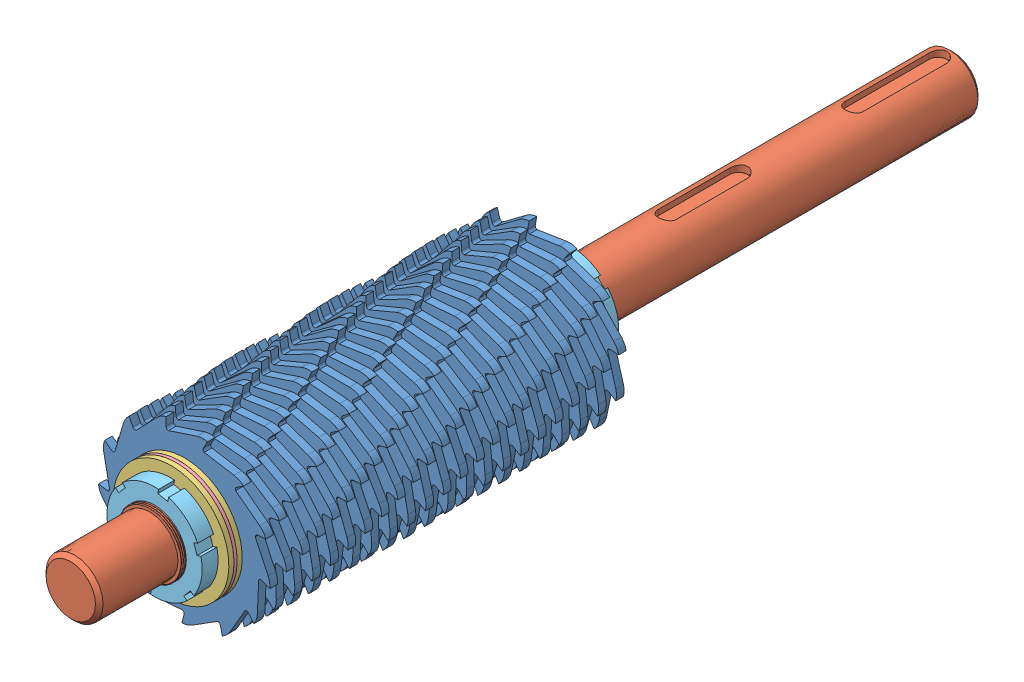
SolidWorks assembly SHRPRO-V1 1130.00-A Shaft 2 assembly, configuration Predeterminado. Lengths in mm.
Overall size (185.42 185.23 695).
76 component instances, 5 part files, 20 mates.
Components (placement in the parent):
- SHRPRO-V1 1130.01-A 13 Teeth blade-1: SHRPRO-V1 1130.01-A 13 Teeth blade [13 Blade] at (0 0 -137.5) x (0 0 -1) z (0.5 0.866025 0) size (6 134.43 135.04)
- SHRPRO-V1 1130.02-A Shaft 2-1: SHRPRO-V1 1130.02-A Shaft 2 [Predeterminado] at origin size (57.74 51.65 695)
- SHRPRO-V1 1120.14-A Spacer 4mm-1: SHRPRO-V1 1120.14-A Spacer 4mm [Défaut] at (0 0 -147) x (0 1 0) z (0 0 1) size (91 91 4)
- SHRPRO-V1 1120.15-A Spacer 2,5mm-1: SHRPRO-V1 1120.15-A Spacer 2,5mm [Défaut] at (0 0 -143) x (-0.866025 -0.5 0) z (0 0 1) size (91 91 2.5)
- SHRPRO-V1 1120.14-A Spacer 4mm-27: SHRPRO-V1 1120.14-A Spacer 4mm [Défaut] at (0 0 -151) x (0 1 0) z (0 0 1) size (91 91 4)
- SHRPRO-V1 1120.14-A Spacer 4mm-28: SHRPRO-V1 1120.14-A Spacer 4mm [Défaut] at (0 0 147) x (0 1 0) z (0 0 1) size (91 91 4)
- SHRPRO-V1 DIN 1804 M50x1,5 Slotted round nut-1: SHRPRO-V1 DIN 1804 M50x1,5 Slotted round nut [Default] at (0 0 -164) x (-0.963483 -0.267769 0) z (-0.267769 0.963483 0) size (75 13 74.57)
- SHRPRO-V1 DIN 1804 M50x1,5 Slotted round nut-2: SHRPRO-V1 DIN 1804 M50x1,5 Slotted round nut [Default] at (0 0 164) x (0.656455 0.754365 0) z (-0.754365 0.656455 0) size (75 13 74.57)
- SHRPRO-V1 1130.01-A 13 Teeth blade-2: SHRPRO-V1 1130.01-A 13 Teeth blade [13 Blade] at (0 0 -125) x (0 0 -1) z (1 0 0) size (6 134.43 135.04)
- SHRPRO-V1 1130.01-A 13 Teeth blade-3: SHRPRO-V1 1130.01-A 13 Teeth blade [13 Blade] at (0 0 -112.5) x (0 0 -1) z (0.5 -0.866025 0) size (6 134.43 135.04)
- SHRPRO-V1 1130.01-A 13 Teeth blade-4: SHRPRO-V1 1130.01-A 13 Teeth blade [13 Blade] at (0 0 -100) x (0 0 -1) z (-0.5 -0.866025 0) size (6 134.43 135.04)
- SHRPRO-V1 1130.01-A 13 Teeth blade-5: SHRPRO-V1 1130.01-A 13 Teeth blade [13 Blade] at (0 0 -87.5) x (0 0 -1) z (-1 0 0) size (6 134.43 135.04)
- SHRPRO-V1 1130.01-A 13 Teeth blade-6: SHRPRO-V1 1130.01-A 13 Teeth blade [13 Blade] at (0 0 -75) x (0 0 -1) z (-0.5 0.866025 0) size (6 134.43 135.04)
- SHRPRO-V1 1130.01-A 13 Teeth blade-7: SHRPRO-V1 1130.01-A 13 Teeth blade [13 Blade] at (0 0 -62.5) x (0 0 -1) z (0.5 0.866025 0) size (6 134.43 135.04)
- SHRPRO-V1 1130.01-A 13 Teeth blade-8: SHRPRO-V1 1130.01-A 13 Teeth blade [13 Blade] at (0 0 -50) x (0 0 -1) z (1 0 0) size (6 134.43 135.04)
- SHRPRO-V1 1130.01-A 13 Teeth blade-9: SHRPRO-V1 1130.01-A 13 Teeth blade [13 Blade] at (0 0 -37.5) x (0 0 -1) z (0.5 -0.866025 0) size (6 134.43 135.04)
- SHRPRO-V1 1130.01-A 13 Teeth blade-10: SHRPRO-V1 1130.01-A 13 Teeth blade [13 Blade] at (0 0 -25) x (0 0 -1) z (-0.5 -0.866025 0) size (6 134.43 135.04)
- SHRPRO-V1 1130.01-A 13 Teeth blade-11: SHRPRO-V1 1130.01-A 13 Teeth blade [13 Blade] at (0 0 -12.5) x (0 0 -1) z (-1 0 0) size (6 134.43 135.04)
- SHRPRO-V1 1130.01-A 13 Teeth blade-12: SHRPRO-V1 1130.01-A 13 Teeth blade [13 Blade] x (0 0 -1) z (-0.5 0.866025 0) size (6 134.43 135.04)
- SHRPRO-V1 1130.01-A 13 Teeth blade-13: SHRPRO-V1 1130.01-A 13 Teeth blade [13 Blade] at (0 0 12.5) x (0 0 -1) z (0.5 0.866025 0) size (6 134.43 135.04)
- SHRPRO-V1 1130.01-A 13 Teeth blade-14: SHRPRO-V1 1130.01-A 13 Teeth blade [13 Blade] at (0 0 25) x (0 0 -1) z (1 0 0) size (6 134.43 135.04)
- SHRPRO-V1 1130.01-A 13 Teeth blade-15: SHRPRO-V1 1130.01-A 13 Teeth blade [13 Blade] at (0 0 37.5) x (0 0 -1) z (0.5 -0.866025 0) size (6 134.43 135.04)
- SHRPRO-V1 1130.01-A 13 Teeth blade-16: SHRPRO-V1 1130.01-A 13 Teeth blade [13 Blade] at (0 0 50) x (0 0 -1) z (-0.5 -0.866025 0) size (6 134.43 135.04)
- SHRPRO-V1 1130.01-A 13 Teeth blade-17: SHRPRO-V1 1130.01-A 13 Teeth blade [13 Blade] at (0 0 62.5) x (0 0 -1) z (-1 0 0) size (6 134.43 135.04)
- SHRPRO-V1 1130.01-A 13 Teeth blade-18: SHRPRO-V1 1130.01-A 13 Teeth blade [13 Blade] at (0 0 75) x (0 0 -1) z (-0.5 0.866025 0) size (6 134.43 135.04)
- SHRPRO-V1 1130.01-A 13 Teeth blade-19: SHRPRO-V1 1130.01-A 13 Teeth blade [13 Blade] at (0 0 87.5) x (0 0 -1) z (0.5 0.866025 0) size (6 134.43 135.04)
- SHRPRO-V1 1130.01-A 13 Teeth blade-20: SHRPRO-V1 1130.01-A 13 Teeth blade [13 Blade] at (0 0 100) x (0 0 -1) z (1 0 0) size (6 134.43 135.04)
- SHRPRO-V1 1130.01-A 13 Teeth blade-21: SHRPRO-V1 1130.01-A 13 Teeth blade [13 Blade] at (0 0 112.5) x (0 0 -1) z (0.5 -0.866025 0) size (6 134.43 135.04)
- SHRPRO-V1 1130.01-A 13 Teeth blade-22: SHRPRO-V1 1130.01-A 13 Teeth blade [13 Blade] at (0 0 125) x (0 0 -1) z (-0.5 -0.866025 0) size (6 134.43 135.04)
- SHRPRO-V1 1130.01-A 13 Teeth blade-23: SHRPRO-V1 1130.01-A 13 Teeth blade [13 Blade] at (0 0 137.5) x (0 0 -1) z (-1 0 0) size (6 134.43 135.04)
- SHRPRO-V1 1120.15-A Spacer 2,5mm-2: SHRPRO-V1 1120.15-A Spacer 2,5mm [Défaut] at (0 0 -130.5) x (-0.866025 -0.5 0) z (0 0 1) size (91 91 2.5)
- SHRPRO-V1 1120.15-A Spacer 2,5mm-3: SHRPRO-V1 1120.15-A Spacer 2,5mm [Défaut] at (0 0 -118) x (-0.866025 -0.5 0) z (0 0 1) size (91 91 2.5)
- SHRPRO-V1 1120.15-A Spacer 2,5mm-4: SHRPRO-V1 1120.15-A Spacer 2,5mm [Défaut] at (0 0 -105.5) x (-0.866025 -0.5 0) z (0 0 1) size (91 91 2.5)
- SHRPRO-V1 1120.15-A Spacer 2,5mm-5: SHRPRO-V1 1120.15-A Spacer 2,5mm [Défaut] at (0 0 -93) x (-0.866025 -0.5 0) z (0 0 1) size (91 91 2.5)
- SHRPRO-V1 1120.15-A Spacer 2,5mm-6: SHRPRO-V1 1120.15-A Spacer 2,5mm [Défaut] at (0 0 -80.5) x (-0.866025 -0.5 0) z (0 0 1) size (91 91 2.5)
- SHRPRO-V1 1120.15-A Spacer 2,5mm-7: SHRPRO-V1 1120.15-A Spacer 2,5mm [Défaut] at (0 0 -68) x (-0.866025 -0.5 0) z (0 0 1) size (91 91 2.5)
- SHRPRO-V1 1120.15-A Spacer 2,5mm-8: SHRPRO-V1 1120.15-A Spacer 2,5mm [Défaut] at (0 0 -55.5) x (-0.866025 -0.5 0) z (0 0 1) size (91 91 2.5)
- SHRPRO-V1 1120.15-A Spacer 2,5mm-9: SHRPRO-V1 1120.15-A Spacer 2,5mm [Défaut] at (0 0 -43) x (-0.866025 -0.5 0) z (0 0 1) size (91 91 2.5)
- SHRPRO-V1 1120.15-A Spacer 2,5mm-10: SHRPRO-V1 1120.15-A Spacer 2,5mm [Défaut] at (0 0 -30.5) x (-0.866025 -0.5 0) z (0 0 1) size (91 91 2.5)
- SHRPRO-V1 1120.15-A Spacer 2,5mm-11: SHRPRO-V1 1120.15-A Spacer 2,5mm [Défaut] at (0 0 -18) x (-0.866025 -0.5 0) z (0 0 1) size (91 91 2.5)
- SHRPRO-V1 1120.15-A Spacer 2,5mm-12: SHRPRO-V1 1120.15-A Spacer 2,5mm [Défaut] at (0 0 -5.5) x (-0.866025 -0.5 0) z (0 0 1) size (91 91 2.5)
- SHRPRO-V1 1120.15-A Spacer 2,5mm-13: SHRPRO-V1 1120.15-A Spacer 2,5mm [Défaut] at (0 0 7) x (-0.866025 -0.5 0) z (0 0 1) size (91 91 2.5)
- SHRPRO-V1 1120.15-A Spacer 2,5mm-14: SHRPRO-V1 1120.15-A Spacer 2,5mm [Défaut] at (0 0 19.5) x (-0.866025 -0.5 0) z (0 0 1) size (91 91 2.5)
- SHRPRO-V1 1120.15-A Spacer 2,5mm-15: SHRPRO-V1 1120.15-A Spacer 2,5mm [Défaut] at (0 0 32) x (-0.866025 -0.5 0) z (0 0 1) size (91 91 2.5)
- SHRPRO-V1 1120.15-A Spacer 2,5mm-16: SHRPRO-V1 1120.15-A Spacer 2,5mm [Défaut] at (0 0 44.5) x (-0.866025 -0.5 0) z (0 0 1) size (91 91 2.5)
- SHRPRO-V1 1120.15-A Spacer 2,5mm-17: SHRPRO-V1 1120.15-A Spacer 2,5mm [Défaut] at (0 0 57) x (-0.866025 -0.5 0) z (0 0 1) size (91 91 2.5)
- SHRPRO-V1 1120.15-A Spacer 2,5mm-18: SHRPRO-V1 1120.15-A Spacer 2,5mm [Défaut] at (0 0 69.5) x (-0.866025 -0.5 0) z (0 0 1) size (91 91 2.5)
- SHRPRO-V1 1120.15-A Spacer 2,5mm-19: SHRPRO-V1 1120.15-A Spacer 2,5mm [Défaut] at (0 0 82) x (-0.866025 -0.5 0) z (0 0 1) size (91 91 2.5)
- SHRPRO-V1 1120.15-A Spacer 2,5mm-20: SHRPRO-V1 1120.15-A Spacer 2,5mm [Défaut] at (0 0 94.5) x (-0.866025 -0.5 0) z (0 0 1) size (91 91 2.5)
- SHRPRO-V1 1120.15-A Spacer 2,5mm-21: SHRPRO-V1 1120.15-A Spacer 2,5mm [Défaut] at (0 0 107) x (-0.866025 -0.5 0) z (0 0 1) size (91 91 2.5)
- SHRPRO-V1 1120.15-A Spacer 2,5mm-22: SHRPRO-V1 1120.15-A Spacer 2,5mm [Défaut] at (0 0 119.5) x (-0.866025 -0.5 0) z (0 0 1) size (91 91 2.5)
- SHRPRO-V1 1120.15-A Spacer 2,5mm-23: SHRPRO-V1 1120.15-A Spacer 2,5mm [Défaut] at (0 0 132) x (-0.866025 -0.5 0) z (0 0 1) size (91 91 2.5)
- SHRPRO-V1 1120.15-A Spacer 2,5mm-24: SHRPRO-V1 1120.15-A Spacer 2,5mm [Défaut] at (0 0 144.5) x (-0.866025 -0.5 0) z (0 0 1) size (91 91 2.5)
- SHRPRO-V1 1120.14-A Spacer 4mm-4: SHRPRO-V1 1120.14-A Spacer 4mm [Défaut] at (0 0 -134.5) x (0 1 0) z (0 0 1) size (91 91 4)
- SHRPRO-V1 1120.14-A Spacer 4mm-5: SHRPRO-V1 1120.14-A Spacer 4mm [Défaut] at (0 0 -122) x (0 1 0) z (0 0 1) size (91 91 4)
- SHRPRO-V1 1120.14-A Spacer 4mm-6: SHRPRO-V1 1120.14-A Spacer 4mm [Défaut] at (0 0 -109.5) x (0 1 0) z (0 0 1) size (91 91 4)
- SHRPRO-V1 1120.14-A Spacer 4mm-7: SHRPRO-V1 1120.14-A Spacer 4mm [Défaut] at (0 0 -97) x (0 1 0) z (0 0 1) size (91 91 4)
- SHRPRO-V1 1120.14-A Spacer 4mm-8: SHRPRO-V1 1120.14-A Spacer 4mm [Défaut] at (0 0 -84.5) x (0 1 0) z (0 0 1) size (91 91 4)
- SHRPRO-V1 1120.14-A Spacer 4mm-9: SHRPRO-V1 1120.14-A Spacer 4mm [Défaut] at (0 0 -72) x (0 1 0) z (0 0 1) size (91 91 4)
- SHRPRO-V1 1120.14-A Spacer 4mm-10: SHRPRO-V1 1120.14-A Spacer 4mm [Défaut] at (0 0 -59.5) x (0 1 0) z (0 0 1) size (91 91 4)
- SHRPRO-V1 1120.14-A Spacer 4mm-11: SHRPRO-V1 1120.14-A Spacer 4mm [Défaut] at (0 0 -47) x (0 1 0) z (0 0 1) size (91 91 4)
- SHRPRO-V1 1120.14-A Spacer 4mm-12: SHRPRO-V1 1120.14-A Spacer 4mm [Défaut] at (0 0 -34.5) x (0 1 0) z (0 0 1) size (91 91 4)
- SHRPRO-V1 1120.14-A Spacer 4mm-13: SHRPRO-V1 1120.14-A Spacer 4mm [Défaut] at (0 0 -22) x (0 1 0) z (0 0 1) size (91 91 4)
- SHRPRO-V1 1120.14-A Spacer 4mm-14: SHRPRO-V1 1120.14-A Spacer 4mm [Défaut] at (0 0 -9.5) x (0 1 0) z (0 0 1) size (91 91 4)
- SHRPRO-V1 1120.14-A Spacer 4mm-15: SHRPRO-V1 1120.14-A Spacer 4mm [Défaut] at (0 0 3) x (0 1 0) z (0 0 1) size (91 91 4)
- SHRPRO-V1 1120.14-A Spacer 4mm-16: SHRPRO-V1 1120.14-A Spacer 4mm [Défaut] at (0 0 15.5) x (0 1 0) z (0 0 1) size (91 91 4)
- SHRPRO-V1 1120.14-A Spacer 4mm-17: SHRPRO-V1 1120.14-A Spacer 4mm [Défaut] at (0 0 28) x (0 1 0) z (0 0 1) size (91 91 4)
- SHRPRO-V1 1120.14-A Spacer 4mm-18: SHRPRO-V1 1120.14-A Spacer 4mm [Défaut] at (0 0 40.5) x (0 1 0) z (0 0 1) size (91 91 4)
- SHRPRO-V1 1120.14-A Spacer 4mm-19: SHRPRO-V1 1120.14-A Spacer 4mm [Défaut] at (0 0 53) x (0 1 0) z (0 0 1) size (91 91 4)
- SHRPRO-V1 1120.14-A Spacer 4mm-20: SHRPRO-V1 1120.14-A Spacer 4mm [Défaut] at (0 0 65.5) x (0 1 0) z (0 0 1) size (91 91 4)
- SHRPRO-V1 1120.14-A Spacer 4mm-21: SHRPRO-V1 1120.14-A Spacer 4mm [Défaut] at (0 0 78) x (0 1 0) z (0 0 1) size (91 91 4)
- SHRPRO-V1 1120.14-A Spacer 4mm-22: SHRPRO-V1 1120.14-A Spacer 4mm [Défaut] at (0 0 90.5) x (0 1 0) z (0 0 1) size (91 91 4)
- SHRPRO-V1 1120.14-A Spacer 4mm-23: SHRPRO-V1 1120.14-A Spacer 4mm [Défaut] at (0 0 103) x (0 1 0) z (0 0 1) size (91 91 4)
- SHRPRO-V1 1120.14-A Spacer 4mm-24: SHRPRO-V1 1120.14-A Spacer 4mm [Défaut] at (0 0 115.5) x (0 1 0) z (0 0 1) size (91 91 4)
- SHRPRO-V1 1120.14-A Spacer 4mm-25: SHRPRO-V1 1120.14-A Spacer 4mm [Défaut] at (0 0 128) x (0 1 0) z (0 0 1) size (91 91 4)
- SHRPRO-V1 1120.14-A Spacer 4mm-26: SHRPRO-V1 1120.14-A Spacer 4mm [Défaut] at (0 0 140.5) x (0 1 0) z (0 0 1) size (91 91 4)
Mates (geometry in assembly coordinates):
- Coincident70: coincident: line of SHRPRO-V1 1130.02-A Shaft 2-1 through (0 0 264.75) axis (0 0 -1); line of SHRPRO-V1 1130.01-A 13 Teeth blade-1 through (0 0 -132) axis (0 0 -1)
- Parallel38: parallel: plane of SHRPRO-V1 1130.02-A Shaft 2-1 through (28.8675 0 150) normal (0.866025 0.5 0); plane of SHRPRO-V1 1130.01-A 13 Teeth blade-1 through (14.4626 25.05 -140.5) normal (-0.866025 -0.5 0)
- Coincident234: coincident: plane of SHRPRO-V1 1130.01-A 13 Teeth blade-1 through (0 0 -140.5) normal (0 0 -1); plane of SHRPRO-V1 1120.15-A Spacer 2,5mm-1 through (0 0 -140.5) normal (0 0 1)
- Coincident21: coincident: line of SHRPRO-V1 1130.02-A Shaft 2-1 through (0 0 264.75) axis (0 0 -1); line of SHRPRO-V1 1120.14-A Spacer 4mm-1 through (0 0 -140.7) axis (0 0 -1)
- Coincident22: parallel: plane of SHRPRO-V1 1130.02-A Shaft 2-1 through (14.4338 25 150) normal (0 1 0); plane of SHRPRO-V1 1120.14-A Spacer 4mm-1 through (14.4626 25.05 -143) normal (0 -1 0)
- Coincident111: coincident: plane of SHRPRO-V1 1120.14-A Spacer 4mm-1 through (0 0 -143) normal (0 0 1); plane of SHRPRO-V1 1120.15-A Spacer 2,5mm-1 through (0 0 -143) normal (0 0 -1)
- Coincident238: coincident: plane of SHRPRO-V1 1120.14-A Spacer 4mm-1 through (0 0 -147) normal (0 0 -1); plane of SHRPRO-V1 1120.14-A Spacer 4mm-27 through (0 0 -147) normal (0 0 1)
- Coincident109: coincident: line of SHRPRO-V1 1130.02-A Shaft 2-1 through (0 0 264.75) axis (0 0 -1); line of SHRPRO-V1 1120.15-A Spacer 2,5mm-1 through (0 0 -136.7) axis (0 0 -1)
- Parallel41: parallel: plane of SHRPRO-V1 1130.02-A Shaft 2-1 through (-14.4338 25 150) normal (-0.866025 0.5 0); plane of SHRPRO-V1 1120.15-A Spacer 2,5mm-1 through (-14.4626 25.05 -140.5) normal (0.866025 -0.5 0)
- Concentric109: concentric: cylinder of SHRPRO-V1 1130.02-A Shaft 2-1 through (0 0 265.4923) axis (0 0 1) radius 22.5; cylinder of SHRPRO-V1 DIN 1804 M50x1,5 Slotted round nut-1 through (0 0 -151) axis (0 0 1) radius 24.25
- Coincident242: coincident: plane of SHRPRO-V1 DIN 1804 M50x1,5 Slotted round nut-1 through (0 0 -151) normal (0 0 1); plane of SHRPRO-V1 1120.14-A Spacer 4mm-27 through (0 0 -151) normal (0 0 -1)
- Concentric110: concentric: cylinder of SHRPRO-V1 1130.02-A Shaft 2-1 through (0 0 265.4923) axis (0 0 1) radius 22.5; cylinder of SHRPRO-V1 DIN 1804 M50x1,5 Slotted round nut-2 through (0 0 151) axis (0 0 -1) radius 24.25
- Coincident241: coincident: plane of SHRPRO-V1 1120.14-A Spacer 4mm-28 through (0 0 151) normal (0 0 1); plane of SHRPRO-V1 DIN 1804 M50x1,5 Slotted round nut-2 through (0 0 151) normal (0 0 -1)
- Coincident237: coincident: line of SHRPRO-V1 1130.02-A Shaft 2-1 through (0 0 264.75) axis (0 0 -1); line of SHRPRO-V1 1120.14-A Spacer 4mm-27 through (0 0 -144.7) axis (0 0 -1)
- Coincident239: coincident: line of SHRPRO-V1 1130.02-A Shaft 2-1 through (0 0 264.75) axis (0 0 -1); line of SHRPRO-V1 1120.14-A Spacer 4mm-28 through (0 0 153.3) axis (0 0 -1)
- Coincident286: coincident: plane of SHRPRO-V1 1120.14-A Spacer 4mm-28 through (0 0 147) normal (0 0 -1); plane of SHRPRO-V1 1120.15-A Spacer 2,5mm-24 through (0 0 147) normal (0 0 1)
- Parallel42: parallel: plane of SHRPRO-V1 1130.02-A Shaft 2-1 through (14.4338 -25 150) normal (0.866025 -0.5 0); plane of SHRPRO-V1 1120.14-A Spacer 4mm-28 through (14.4626 -25.05 151) normal (-0.866025 0.5 0)
- Width1: width: plane of SHRPRO-V1 1130.02-A Shaft 2-1 through (0 0 150) normal (0 0 1); plane of SHRPRO-V1 1130.02-A Shaft 2-1 through (0 0 -150) normal (0 0 -1); plane of SHRPRO-V1 1120.14-A Spacer 4mm-27 through (0 0 -151) normal (0 0 -1); plane of SHRPRO-V1 1120.14-A Spacer 4mm-28 through (0 0 151) normal (0 0 1)
- Parallel43: parallel: plane of SHRPRO-V1 1130.02-A Shaft 2-1 through (14.4338 -25 150) normal (0.866025 -0.5 0); plane of SHRPRO-V1 1120.14-A Spacer 4mm-27 through (14.4626 -25.05 -147) normal (-0.866025 0.5 0)
- Coordinate1: coordinate: point of SHRPRO-V1 1130.02-A Shaft 2-1; point of assembly
